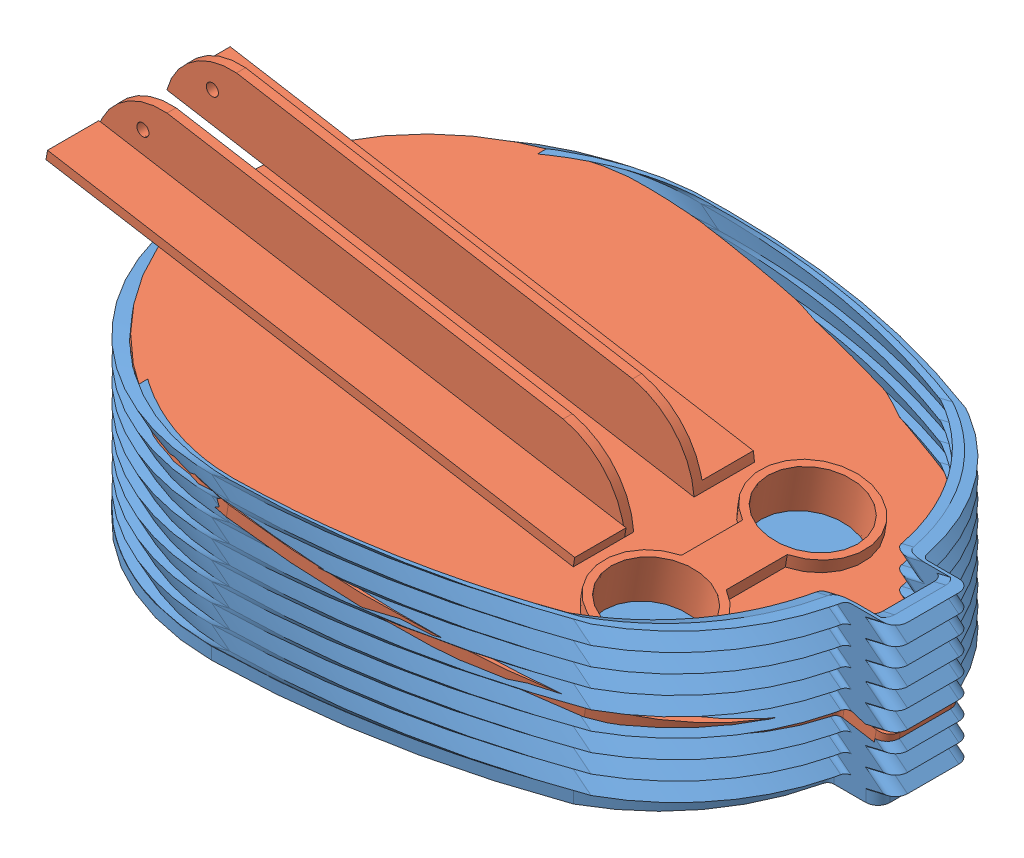
SolidWorks assembly Assem2, configuration Default. Lengths in mm.
Overall size (268.61 87.39 167.56).
2 component instances, 2 part files, 2 mates.
Components (placement in the parent):
- tapa de fuelle-1: tapa de fuelle [Default] at (-74.6208 -21.0988 28.6831) size (241.61 58.14 167.56)
- tapa sup de fuelle-1: tapa sup de fuelle [Default] at (-70.1283 17.7386 28.6831) x (0.986043 -0.166488 0) z (0 0 1) size (265 43.89 160.08)
Mates (geometry in assembly coordinates):
- Concentric1: concentric: cylinder of tapa de fuelle-1 through (16.4066 -13.0988 83.6831) axis (0 0 -1) radius 2; cylinder of tapa sup de fuelle-1 through (16.4066 -13.0988 -5.3169) axis (0 0 1) radius 2
- Coincident1: coincident: plane of tapa de fuelle-1 through (13.4066 -9.0988 53.6831) normal (0 0 -1); plane of tapa sup de fuelle-1 through (12.7825 -16.5436 53.6831) normal (0 0 1)
